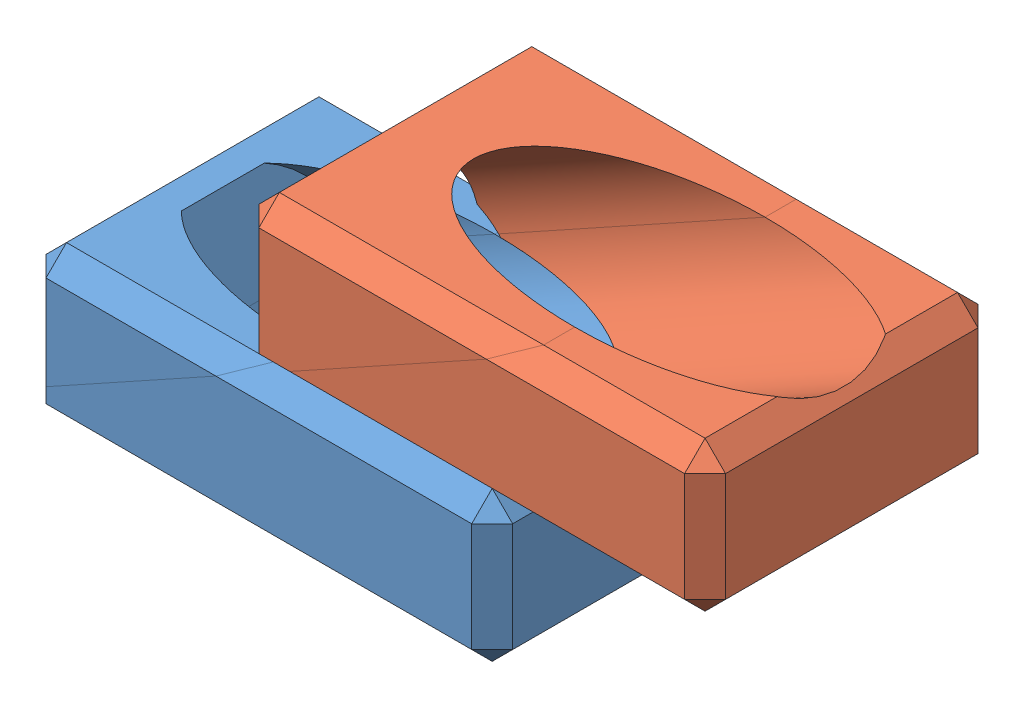
SolidWorks assembly Assem1, configuration Default. Lengths in mm.
Overall size (347.6 182.05 143.36).
3 component instances, 3 part files, 3 mates.
Components (placement in the parent):
- Bottom Block-1: Bottom Block [Default] at origin size (228 73.22 143.36)
- Middle foam block-1: Middle foam block [Default] at (104 73.22 0) size (228 73.22 143.36)
- Arm slot clutter-1: Arm slot clutter [Default] at origin size (307.47 226.78 93) (hidden)
Mates (geometry in assembly coordinates):
- Coincident1: coincident anti-aligned: plane of Foam Block-1 through (0 73.22 0) normal (0 1 0); plane of Middle foam block-1 through (104 73.22 0) normal (0 -1 0)
- Coincident2: coincident aligned: plane of Foam Block-1 through (-114 73.22 71.68) normal (0 0 1); plane of Foam Block-2 through (-10 146.44 71.68) normal (0 0 1)
- Coincident3: coincident: line of Foam Block-2 through (0 136.44 71.68) axis (0 -1 0); plane of assembly through (0 0 0) normal (1 0 0)
